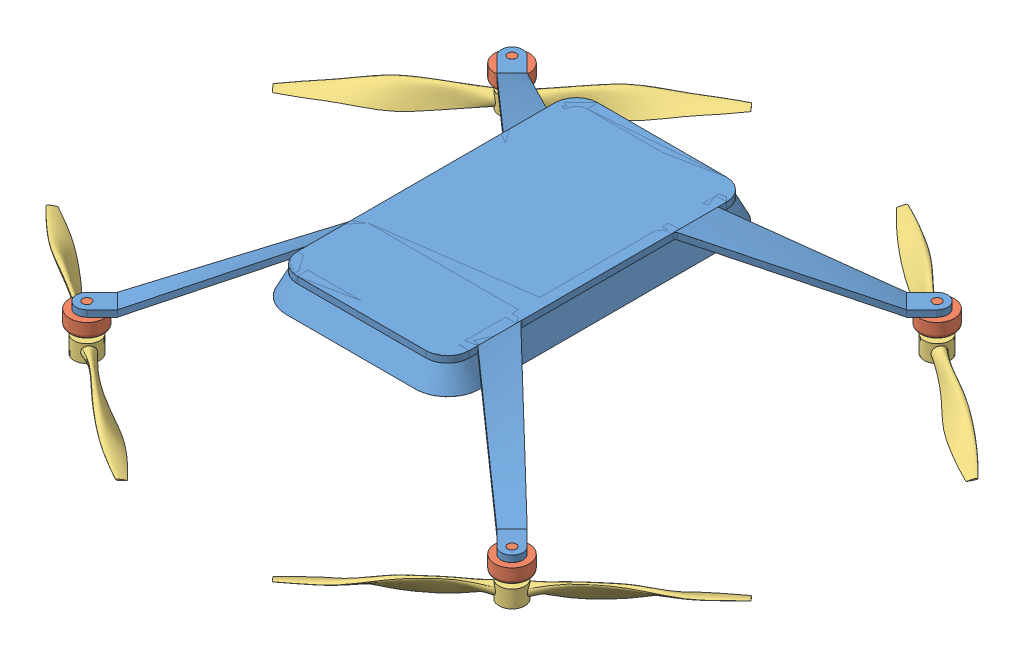
SolidWorks assembly Drone - 2 Assembly, configuration Default. Lengths in mm.
Overall size (331.94 57.38 310.82).
9 component instances, 3 part files, 6 mates.
Components (placement in the parent):
- Base1-1: Base1 [Default] at (69.9788 94.8196 161.0561) size (207.99 38.98 207.99)
- motor-1: motor [Default] at (-29.0162 63.3046 62.0611) x (-0.837169 0 -0.546944) z (-0.546944 0 0.837169) size (16 15 16)
- Propeller-1: Propeller [Default] at (-25.9998 79.3196 59.434) x (-0.656776 0 -0.754086) z (0.754086 0 -0.656776) size (12 10.47 158.02)
- Propeller-2: Propeller [Default] at (165.9574 79.3196 262.6781) x (0.656776 0 0.754086) z (-0.754086 0 0.656776) size (12 10.47 158.02)
- motor-5: motor [Default] at (-29.0162 63.3046 260.051) x (-0.546944 0 0.837169) z (0.837169 0 0.546944) size (16 15 16)
- motor-6: motor [Default] at (168.9737 63.3046 260.051) x (0.837169 0 0.546944) z (0.546944 0 -0.837169) size (16 15 16)
- motor-7: motor [Default] at (168.9737 63.3046 62.0611) x (0.546944 0 -0.837169) z (-0.837169 0 -0.546944) size (16 15 16)
- Propeller-3: Propeller [Default] at (-32.2257 79.3196 257.6638) x (-0.596806 0 0.802386) z (-0.802386 0 -0.596806) size (12 10.47 158.02)
- Propeller-4: Propeller [Default] at (172.1833 79.3196 64.4483) x (0.596806 0 -0.802386) z (0.802386 0 0.596806) size (12 10.47 158.02)
Mates (geometry in assembly coordinates):
- Coincident1: coincident anti-aligned: plane of Base1-1 through (69.9788 93.3196 161.0561) normal (0 -1 0); plane of motor-1 through (-29.0162 93.3196 62.0611) normal (0 1 0)
- Concentric1: concentric aligned: cylinder of Base1-1 through (-29.0162 96.3196 62.0611) axis (0 -1 0) radius 2; cylinder of motor-1 through (-29.0162 96.3196 62.0611) axis (0 -1 0) radius 2
- Concentric2: concentric aligned: cylinder of motor-1 through (-29.0162 17.2284 62.0611) axis (0 -1 0) radius 1.5; cylinder of Propeller-1 through (-29.0162 83.3196 62.0611) axis (0 -1 0) radius 1.5
- Coincident2: coincident anti-aligned: circle of motor-1; circle of Propeller-1
- Concentric3: concentric aligned: cylinder of motor-5 through (-29.0162 17.2284 260.051) axis (0 -1 0) radius 1.5; cylinder of Propeller-3 through (-29.0162 83.3196 260.051) axis (0 -1 0) radius 1.5
- Coincident3: coincident anti-aligned: circle of motor-5; circle of Propeller-3
